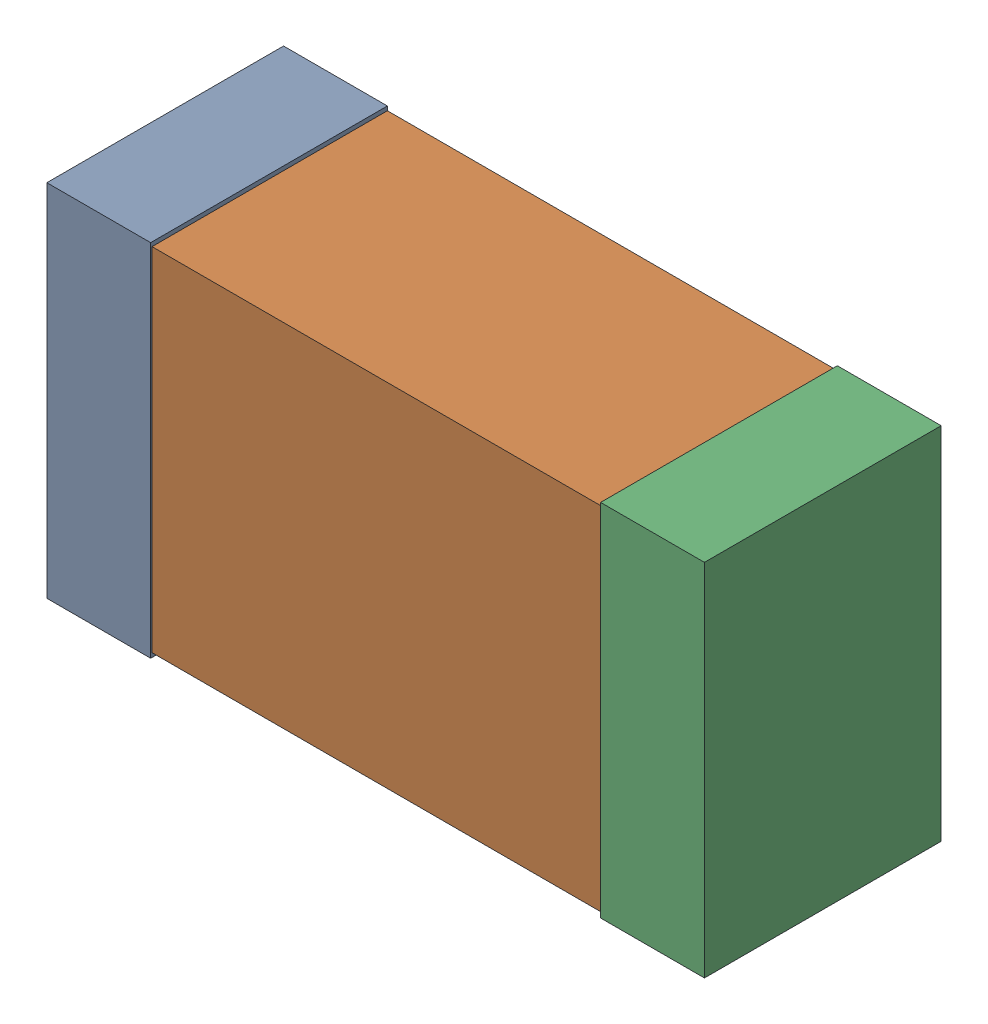
SolidWorks assembly R4Kanaloa_v2.0.0_GPIO_b, configuration Default. Lengths in mm.
Overall size (2.38 1.3 0.85).
6 component instances, 2 part files, 0 mates.
Components (placement in the parent):
- 352877648-1: 352877648 [Default] at (61.738 54.61 0) size (0.38 1.3 0.85)
  - Extruded_14-1: Extruded_14 [Default] at origin size (0.38 1.3 0.85)
- 352877904-1: 352877904 [Default] at (62.738 54.61 0) size (2.2 1.27 0.85)
  - Extruded_18-1: Extruded_18 [Default] at origin size (2.2 1.27 0.85)
- 352877648-2: 352877648 [Default] at (63.738 54.61 0) size (0.38 1.3 0.85)
  - Extruded_14-1: Extruded_14 [Default] at origin size (0.38 1.3 0.85)
